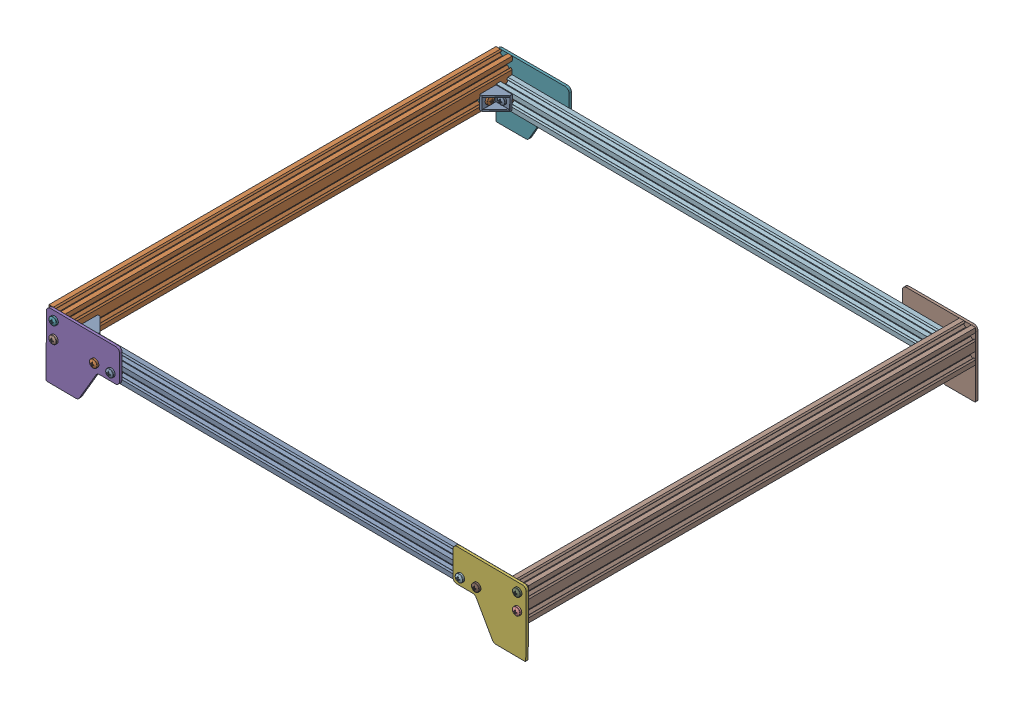
SolidWorks assembly frame, configuration По умолчанию. Lengths in mm.
Overall size (590.6 84.54 563.64).
52 component instances, 7 part files, 101 mates.
Components (placement in the parent):
- 2020 Aluminum Profile_550-3: 2020 Aluminum Profile_550 [По умолчанию] at (869.1226 480.4847 1085.1213) x (0 0 1) z (-0.99997 0.007699 0) size (20 20 550)
- 2040 Aluminum Profile_550_mm-1: 2040 Aluminum Profile_550_mm [По умолчанию] at (309.2932 504.7957 302.3871) x (0.99997 -0.007699 0) z (0 0 1) size (20 40 550)
- 90 Degree Cast Corner for 2020 Extrusion (Ooznest)-1: 90 Degree Cast Corner for 2020 Extrusion (Ooznest) [По умолчанию] at (319.2092 493.8441 1075.1213) x (-0.007699 -0.99997 0) z (0.99997 -0.007699 0) size (17.01 21.05 21.01)
- M5 T-Nut-1: M5 T-Nut [По умолчанию] at (330.8895 484.7539 1077.5213) x (-0.007699 -0.99997 0) z (0 0 -1) size (10 10.5 5)
- M5 T-Nut-2: M5 T-Nut [По умолчанию] at (317.3399 484.8582 1066.1669) x (-0.007699 -0.99997 0) z (0.99997 -0.007699 0) size (10 10.5 5)
- pan cross head_am_B18.6.7M - M5 x 0.8 x 8 Type I Cross Recessed PHMS --8S-1: pan cross head_am_B18.6.7M - M5 x 0.8 x 8 Type I Cross Recessed PHMS --8S [По умолчанию] at (330.8895 484.7539 1068.7213) x (0 0 1) z (-1 0 0) size (11.67 9.5 9.5)
- pan cross head_am_B18.6.7M - M5 x 0.8 x 8 Type I Cross Recessed PHMS --8S-2: pan cross head_am_B18.6.7M - M5 x 0.8 x 8 Type I Cross Recessed PHMS --8S [По умолчанию] at (325.8397 484.7927 1066.1669) x (-0.99997 0.007699 0) z (0.007116 0.924197 0.381849) size (11.67 9.5 9.5)
- M5 T-Nut-3: M5 T-Nut [По умолчанию] at (359.1377 484.4114 1093.3213) x (0 -1 0) z (0 0 1) size (10 10.5 5)
- M5 T-Nut-4: M5 T-Nut [По умолчанию] at (379.1371 484.2574 1093.3213) x (0 -1 0) z (0 0 1) size (10 10.5 5)
- M5 T-Nut-5: M5 T-Nut [По умолчанию] at (829.1238 480.7927 1093.3213) x (0 1 0) z (0 0 1) size (10 10.5 5)
- M5 T-Nut-6: M5 T-Nut [По умолчанию] at (809.1238 480.7927 1093.3213) x (0 -1 0) z (0 0 1) size (10 10.5 5)
- 90 Degree Cast Corner for 2020 Extrusion (Ooznest)-2: 90 Degree Cast Corner for 2020 Extrusion (Ooznest) [По умолчанию] at (319.0783 476.8446 565.1213) x (0.007699 0.99997 0) z (0.99997 -0.007699 0) size (17.01 21.05 21.01)
- M5 T-Nut-7: M5 T-Nut [По умолчанию] at (330.6434 485.2608 563.3213) x (0.007699 0.99997 0) z (0 0 1) size (10 10.5 5)
- 2020 Aluminum Profile_550-2: 2020 Aluminum Profile_550 [По умолчанию] at (310.4341 484.7864 555.1213) x (0 0 -1) z (0.99997 -0.007699 0) size (20 20 550)
- pan cross head_am_B18.6.7M - M5 x 0.8 x 8 Type I Cross Recessed PHMS --8S-3: pan cross head_am_B18.6.7M - M5 x 0.8 x 8 Type I Cross Recessed PHMS --8S [По умолчанию] at (330.6434 485.2608 571.8213) x (0 0 -1) z (1 0 0) size (11.67 9.5 9.5)
- pan cross head_am_B18.6.7M - M5 x 0.8 x 8 Type I Cross Recessed PHMS --8S-4: pan cross head_am_B18.6.7M - M5 x 0.8 x 8 Type I Cross Recessed PHMS --8S [По умолчанию] at (325.8436 485.2978 576.6213) x (-0.99997 0.007699 0) z (-0.007116 -0.924197 0.381849) size (11.67 9.5 9.5)
- M5 T-Nut-8: M5 T-Nut [По умолчанию] at (829.1223 480.4077 547.2213) x (0 -1 0) z (0 0 -1) size (10 10.5 5)
- M5 T-Nut-9: M5 T-Nut [По умолчанию] at (809.1223 480.4077 547.2213) x (0 1 0) z (0 0 -1) size (10 10.5 5)
- M5 T-Nut-10: M5 T-Nut [По умолчанию] at (379.1392 484.7963 546.9213) x (0 1 0) z (0 0 -1) size (10 10.5 5)
- M5 T-Nut-11: M5 T-Nut [По умолчанию] at (359.1392 484.7963 546.9213) x (0 1 0) z (0 0 -1) size (10 10.5 5)
- M5 T-Nut-12: M5 T-Nut [По умолчанию] at (317.0438 485.3655 576.6213) x (0.007699 0.99997 0) z (0.99997 -0.007699 0) size (10 10.5 5)
- 2040 Aluminum Profile_550_mm-2: 2040 Aluminum Profile_550_mm [По умолчанию] at (879.2763 500.4071 1338.0213) x (-0.99997 0.007699 0) z (0 0 -1) size (20 40 550)
- M5 T-Nut-13: M5 T-Nut [По умолчанию] at (871.2238 480.7927 1063.9213) x (0 1 0) z (-1 0 0) size (10 10.5 5)
- pan cross head_am_B18.6.7M - M5 x 0.8 x 8 Type I Cross Recessed PHMS --8S-5: pan cross head_am_B18.6.7M - M5 x 0.8 x 8 Type I Cross Recessed PHMS --8S [По умолчанию] at (857.6238 480.7927 1068.7213) x (0 0 1) z (-1 0 0) size (11.67 9.5 9.5)
- pan cross head_am_B18.6.7M - M5 x 0.8 x 8 Type I Cross Recessed PHMS --8S-6: pan cross head_am_B18.6.7M - M5 x 0.8 x 8 Type I Cross Recessed PHMS --8S [По умолчанию] at (862.4238 480.7927 1063.9213) x (1 0 0) z (0 -0.924225 -0.381849) size (11.67 9.5 9.5)
- pan cross head_am_B18.6.7M - M5 x 0.8 x 8 Type I Cross Recessed PHMS --8S-7: pan cross head_am_B18.6.7M - M5 x 0.8 x 8 Type I Cross Recessed PHMS --8S [По умолчанию] at (857.5886 475.8584 571.8213) x (0 0 -1) z (1 0 0) size (11.67 9.5 9.5)
- pan cross head_am_B18.6.7M - M5 x 0.8 x 8 Type I Cross Recessed PHMS --8S-8: pan cross head_am_B18.6.7M - M5 x 0.8 x 8 Type I Cross Recessed PHMS --8S [По умолчанию] at (862.3894 475.8584 576.6213) x (1 0 0) z (0 0.924225 -0.381849) size (11.67 9.5 9.5)
- M5 T-Nut-14: M5 T-Nut [По умолчанию] at (871.1894 475.8584 576.6213) x (0 -1 0) z (-1 0 0) size (10 10.5 5)
- M5 T-Nut-15: M5 T-Nut [По умолчанию] at (857.5886 475.8584 563.0213) x (0 -1 0) z (0 0 1) size (10 10.5 5)
- M5 T-Nut-16: M5 T-Nut [По умолчанию] at (857.6238 480.7927 1077.5213) x (0 1 0) z (0 0 -1) size (10 10.5 5)
- 90 Degree Cast Corner for 2020 Extrusion (Ooznest)-3: 90 Degree Cast Corner for 2020 Extrusion (Ooznest) [По умолчанию] at (869.1238 489.2927 1075.4213) x (0 -1 0) z (0 0 -1) size (17.01 21.05 21.01)
- 90 Degree Cast Corner for 2020 Extrusion (Ooznest)-4: 90 Degree Cast Corner for 2020 Extrusion (Ooznest) [По умолчанию] at (869.0886 467.3533 565.1213) x (0 1 0) z (0 0 1) size (17.01 21.05 21.01)
- Feet-1: Feet [По умолчанию] at (344.9962 595.9593 1095.2871) x (0.99997 -0.007699 0) z (0 0 1) size (90 80 3)
- Feet-2: Feet [По умолчанию] at (844.9813 592.1097 1098.1213) x (-0.99997 0.007699 0) z (0 0 -1) size (90 80 3)
- pan cross head_am_B18.6.7M - M5 x 0.8 x 10 Type I Cross Recessed PHMS --10S-1: pan cross head_am_B18.6.7M - M5 x 0.8 x 10 Type I Cross Recessed PHMS --10S [По умолчанию] at (309.2932 504.7957 1102.1213) x (0 0 -1) z (1 0 0) size (13.67 9.5 9.5)
- pan cross head_am_B18.6.7M - M5 x 0.8 x 10 Type I Cross Recessed PHMS --10S-2: pan cross head_am_B18.6.7M - M5 x 0.8 x 10 Type I Cross Recessed PHMS --10S [По умолчанию] at (309.1392 484.7963 1102.1213) x (0 0 -1) z (1 0 0) size (13.67 9.5 9.5)
- pan cross head_am_B18.6.7M - M5 x 0.8 x 10 Type I Cross Recessed PHMS --10S-3: pan cross head_am_B18.6.7M - M5 x 0.8 x 10 Type I Cross Recessed PHMS --10S [По умолчанию] at (879.2763 500.4071 1101.8213) x (0 0 -1) z (1 0 0) size (13.67 9.5 9.5)
- pan cross head_am_B18.6.7M - M5 x 0.8 x 10 Type I Cross Recessed PHMS --10S-4: pan cross head_am_B18.6.7M - M5 x 0.8 x 10 Type I Cross Recessed PHMS --10S [По умолчанию] at (879.1223 480.4077 1101.8213) x (0 0 -1) z (1 0 0) size (13.67 9.5 9.5)
- pan cross head_am_B18.6.7M - M5 x 0.8 x 8 Type I Cross Recessed PHMS --8S-9: pan cross head_am_B18.6.7M - M5 x 0.8 x 8 Type I Cross Recessed PHMS --8S [По умолчанию] at (829.1238 480.7927 1102.1213) x (0 0 -1) z (1 0 0) size (11.67 9.5 9.5)
- pan cross head_am_B18.6.7M - M5 x 0.8 x 8 Type I Cross Recessed PHMS --8S-10: pan cross head_am_B18.6.7M - M5 x 0.8 x 8 Type I Cross Recessed PHMS --8S [По умолчанию] at (809.1238 480.7927 1102.1213) x (0 0 -1) z (1 0 0) size (11.67 9.5 9.5)
- pan cross head_am_B18.6.7M - M5 x 0.8 x 8 Type I Cross Recessed PHMS --8S-11: pan cross head_am_B18.6.7M - M5 x 0.8 x 8 Type I Cross Recessed PHMS --8S [По умолчанию] at (379.1371 484.2574 1102.1213) x (0 0 -1) z (1 0 0) size (11.67 9.5 9.5)
- pan cross head_am_B18.6.7M - M5 x 0.8 x 8 Type I Cross Recessed PHMS --8S-12: pan cross head_am_B18.6.7M - M5 x 0.8 x 8 Type I Cross Recessed PHMS --8S [По умолчанию] at (359.1377 484.4114 1102.1213) x (0 0 -1) z (1 0 0) size (11.67 9.5 9.5)
- pan cross head_am_B18.6.7M - M5 x 0.8 x 10 Type I Cross Recessed PHMS --10S-5: pan cross head_am_B18.6.7M - M5 x 0.8 x 10 Type I Cross Recessed PHMS --10S [По умолчанию] at (879.1223 480.4077 538.4213) x (0 0 1) z (1 0 0) size (13.67 9.5 9.5)
- pan cross head_am_B18.6.7M - M5 x 0.8 x 10 Type I Cross Recessed PHMS --10S-6: pan cross head_am_B18.6.7M - M5 x 0.8 x 10 Type I Cross Recessed PHMS --10S [По умолчанию] at (309.1392 504.7963 538.5871) x (0 0 1) z (-1 0 0) size (13.67 9.5 9.5)
- pan cross head_am_B18.6.7M - M5 x 0.8 x 10 Type I Cross Recessed PHMS --10S-7: pan cross head_am_B18.6.7M - M5 x 0.8 x 10 Type I Cross Recessed PHMS --10S [По умолчанию] at (879.1223 500.4077 538.4213) x (0 0 1) z (-1 0 0) size (13.67 9.5 9.5)
- pan cross head_am_B18.6.7M - M5 x 0.8 x 10 Type I Cross Recessed PHMS --10S-8: pan cross head_am_B18.6.7M - M5 x 0.8 x 10 Type I Cross Recessed PHMS --10S [По умолчанию] at (309.1392 484.7963 538.5871) x (0 0 1) z (-1 0 0) size (13.67 9.5 9.5)
- Feet-3: Feet [По умолчанию] at (344.1392 596.2321 542.2871) size (90 80 3)
- Feet-4: Feet [По умолчанию] at (844.1223 591.8435 545.1213) x (-1 0 0) z (0 0 -1) size (90 80 3)
- pan cross head_am_B18.6.7M - M5 x 0.8 x 8 Type I Cross Recessed PHMS --8S-13: pan cross head_am_B18.6.7M - M5 x 0.8 x 8 Type I Cross Recessed PHMS --8S [По умолчанию] at (829.1223 480.4077 538.4213) x (0 0 1) z (-1 0 0) size (11.67 9.5 9.5)
- pan cross head_am_B18.6.7M - M5 x 0.8 x 8 Type I Cross Recessed PHMS --8S-14: pan cross head_am_B18.6.7M - M5 x 0.8 x 8 Type I Cross Recessed PHMS --8S [По умолчанию] at (359.1392 484.7963 538.5871) x (0 0 1) z (-1 0 0) size (11.67 9.5 9.5)
- pan cross head_am_B18.6.7M - M5 x 0.8 x 8 Type I Cross Recessed PHMS --8S-15: pan cross head_am_B18.6.7M - M5 x 0.8 x 8 Type I Cross Recessed PHMS --8S [По умолчанию] at (379.1392 484.7963 538.5871) x (0 0 1) z (-1 0 0) size (11.67 9.5 9.5)
- pan cross head_am_B18.6.7M - M5 x 0.8 x 8 Type I Cross Recessed PHMS --8S-16: pan cross head_am_B18.6.7M - M5 x 0.8 x 8 Type I Cross Recessed PHMS --8S [По умолчанию] at (809.1223 480.4077 538.4213) x (0 0 1) z (-1 0 0) size (11.67 9.5 9.5)
Mates (geometry in assembly coordinates):
- Совпадение1: coincident anti-aligned: plane of 2040 Aluminum Profile_550_mm-2 through (879.2763 500.4071 545.1213) normal (0 0 -1); plane of Feet-4 through (884.1223 505.4077 545.1213) normal (0 0 1)
- Совпадение2: coincident anti-aligned: plane of 2040 Aluminum Profile_550_mm-2 through (879.2763 500.4071 1095.1213) normal (0 0 1); plane of Feet-2 through (884.3147 505.3685 1095.1213) normal (0 0 -1)
- Совпадение3: coincident anti-aligned: plane of 2020 Aluminum Profile_550-3 through (319.1389 484.7193 1085.1213) normal (-0.99997 0.007699 0); plane of 2040 Aluminum Profile_550_mm-1 through (319.0619 474.7196 545.2871) normal (0.99997 -0.007699 0)
- Совпадение4: coincident anti-aligned: plane of 2040 Aluminum Profile_550_mm-1 through (309.2932 504.7957 1095.2871) normal (0 0 1); plane of Feet-1 through (304.3319 509.8341 1095.2871) normal (0 0 -1)
- Совпадение5: coincident anti-aligned: plane of 2020 Aluminum Profile_550-3 through (869.1226 480.4847 1085.1213) normal (0.99997 -0.007699 0); plane of 2040 Aluminum Profile_550_mm-2 through (869.0456 470.485 1095.1213) normal (-0.99997 0.007699 0)
- Совпадение8: coincident aligned: circle of 2040 Aluminum Profile_550_mm-2; circle of Feet-2
- Совпадение9: coincident anti-aligned: plane of 2020 Aluminum Profile_550-3 through (319.163 487.8442 1093.3213) normal (0 0 -1); plane of M5 T-Nut-6 through (814.3738 483.7927 1093.3213) normal (0 0 1)
- Совпадение11: coincident anti-aligned: plane of 2020 Aluminum Profile_550-3 through (319.1037 480.1395 1095.1213) normal (0 0 1); plane of Feet-2 through (884.3147 505.3685 1095.1213) normal (0 0 -1)
- Совпадение14: coincident anti-aligned: plane of 2040 Aluminum Profile_550_mm-2 through (879.2763 500.4071 545.1213) normal (0 0 -1); plane of Feet-4 through (884.1223 505.4077 545.1213) normal (0 0 1)
- Совпадение15: coincident aligned: circle of 2040 Aluminum Profile_550_mm-2; circle of Feet-4
- Совпадение16: coincident: plane of 2040 Aluminum Profile_550_mm-1 through (309.2932 504.7957 545.2871) normal (0 0 -1); plane of Feet-3 through (304.1392 509.7963 545.2871) normal (0 0 1)
- Совпадение17: coincident: cylinder of 2040 Aluminum Profile_550_mm-1 through (309.1392 484.7963 545.2871) axis (0 0 1) radius 2.55; circle of Feet-3
- Совпадение23: coincident: plane of Feet-3 through (304.1392 509.7963 542.2871) normal (0 0 -1); plane of pan cross head_am_B18.6.7M - M5 x 0.8 x 8 Type I Cross Recessed PHMS --8S-15 through (379.1392 487.2963 542.2871) normal (0 0 1)
- Совпадение25: coincident: plane of Feet-3 through (304.1392 509.7963 542.2871) normal (0 0 -1); plane of pan cross head_am_B18.6.7M - M5 x 0.8 x 8 Type I Cross Recessed PHMS --8S-14 through (359.1392 487.2963 542.2871) normal (0 0 1)
- Совпадение26: coincident: line of 2020 Aluminum Profile_550-2 through (860.4419 483.6766 546.9213) axis (-0.99997 0.007699 0); plane of M5 T-Nut-10 through (384.3892 489.7963 546.9213) normal (0 0 -1)
- Совпадение28: coincident anti-aligned: plane of pan cross head_am_B18.6.7M - M5 x 0.8 x 10 Type I Cross Recessed PHMS --10S-6 through (309.1392 507.2963 542.2871) normal (0 0 1); plane of Feet-3 through (304.1392 509.7963 542.2871) normal (0 0 -1)
- Совпадение30: coincident anti-aligned: plane of pan cross head_am_B18.6.7M - M5 x 0.8 x 10 Type I Cross Recessed PHMS --10S-8 through (309.1392 487.2963 542.2871) normal (0 0 1); plane of Feet-3 through (304.1392 509.7963 542.2871) normal (0 0 -1)
- Совпадение32: coincident anti-aligned: plane of pan cross head_am_B18.6.7M - M5 x 0.8 x 10 Type I Cross Recessed PHMS --10S-7 through (879.1223 502.9077 542.1213) normal (0 0 1); plane of Feet-4 through (884.1223 505.4077 542.1213) normal (0 0 -1)
- Параллельность11: parallel anti-aligned: plane of pan cross head_am_B18.6.7M - M5 x 0.8 x 10 Type I Cross Recessed PHMS --10S-5 through (879.1223 477.9077 542.1213) normal (0 0 1); plane of Feet-4 through (884.1223 505.4077 542.1213) normal (0 0 -1)
- Совпадение34: coincident: plane of M5 T-Nut-10 through (384.3892 487.7963 545.9213) normal (0 0 -1); plane of M5 T-Nut-11 through (364.3892 487.7963 545.9213) normal (0 0 -1)
- Расстояние1: distance = 3.25 mm aligned: plane of 90 Degree Cast Corner for 2020 Extrusion (Ooznest)-2 through (339.0777 476.6906 565.1213) normal (0.99997 -0.007699 0); plane of M5 T-Nut-7 through (335.8933 485.2204 562.0708) normal (0.99997 -0.007699 0)
- Расстояние4: distance = 3.25 mm: plane of 90 Degree Cast Corner for 2020 Extrusion (Ooznest)-2 through (329.1434 485.2673 585.1213) normal (0 0 1); plane of M5 T-Nut-12 through (315.7934 485.3752 581.8713) normal (0 0 1)
- Концентричный2: concentric aligned: circle of pan cross head_am_B18.6.7M - M5 x 0.8 x 8 Type I Cross Recessed PHMS --8S-4; circle of M5 T-Nut-12
- Концентричный3: concentric aligned: circle of M5 T-Nut-7; circle of pan cross head_am_B18.6.7M - M5 x 0.8 x 8 Type I Cross Recessed PHMS --8S-3
- Совпадение40: coincident: plane of 90 Degree Cast Corner for 2020 Extrusion (Ooznest)-2 through (330.6434 485.2558 568.1213) normal (0 0 1); plane of pan cross head_am_B18.6.7M - M5 x 0.8 x 8 Type I Cross Recessed PHMS --8S-3 through (330.6434 487.7608 568.1213) normal (0 0 -1)
- Совпадение43: coincident: plane of M5 T-Nut-7 through (325.3705 482.3013 563.3213) normal (0 0 1); line of 2020 Aluminum Profile_550-2 through (860.3938 477.4268 563.3213) axis (-0.99997 0.007699 0)
- Совпадение44: coincident anti-aligned: plane of Feet-2 through (884.3147 505.3685 1098.1213) normal (0 0 1); plane of pan cross head_am_B18.6.7M - M5 x 0.8 x 10 Type I Cross Recessed PHMS --10S-3 through (879.2763 502.9071 1098.1213) normal (0 0 -1)
- Совпадение45: coincident aligned: plane of pan cross head_am_B18.6.7M - M5 x 0.8 x 10 Type I Cross Recessed PHMS --10S-3 through (879.2763 502.9071 1098.1213) normal (0 0 -1); plane of pan cross head_am_B18.6.7M - M5 x 0.8 x 10 Type I Cross Recessed PHMS --10S-4 through (879.1223 482.9077 1098.1213) normal (0 0 -1)
- Концентричный4: concentric anti-aligned: circle of Feet-2; circle of pan cross head_am_B18.6.7M - M5 x 0.8 x 10 Type I Cross Recessed PHMS --10S-3
- Концентричный5: concentric anti-aligned: circle of Feet-2; circle of pan cross head_am_B18.6.7M - M5 x 0.8 x 10 Type I Cross Recessed PHMS --10S-4
- Концентричный6: concentric: circle of M5 T-Nut-6; circle of pan cross head_am_B18.6.7M - M5 x 0.8 x 8 Type I Cross Recessed PHMS --8S-10
- Расстояние5: distance = 1.1 mm: plane of pan cross head_am_B18.6.7M - M5 x 0.8 x 8 Type I Cross Recessed PHMS --8S-10 through (809.1238 483.2927 1090.4213) normal (0 0 -1); plane of M5 T-Nut-6 through (814.3738 483.2927 1089.3213) normal (0 0 -1)
- Расстояние6: distance = 1.1 mm: plane of M5 T-Nut-5 through (823.8738 478.2927 1089.3213) normal (0 0 -1); plane of pan cross head_am_B18.6.7M - M5 x 0.8 x 8 Type I Cross Recessed PHMS --8S-9 through (829.1238 483.2927 1090.4213) normal (0 0 -1)
- Концентричный7: concentric: circle of M5 T-Nut-5; circle of pan cross head_am_B18.6.7M - M5 x 0.8 x 8 Type I Cross Recessed PHMS --8S-9
- Концентричный8: concentric anti-aligned: circle of Feet-2; circle of pan cross head_am_B18.6.7M - M5 x 0.8 x 8 Type I Cross Recessed PHMS --8S-9
- Концентричный9: concentric aligned: circle of pan cross head_am_B18.6.7M - M5 x 0.8 x 10 Type I Cross Recessed PHMS --10S-5; circle of Feet-4
- Совпадение46: coincident anti-aligned: plane of pan cross head_am_B18.6.7M - M5 x 0.8 x 10 Type I Cross Recessed PHMS --10S-5 through (879.1223 477.9077 542.1213) normal (0 0 1); plane of Feet-4 through (884.1223 505.4077 542.1213) normal (0 0 -1)
- Концентричный10: concentric anti-aligned: circle of M5 T-Nut-9; circle of pan cross head_am_B18.6.7M - M5 x 0.8 x 8 Type I Cross Recessed PHMS --8S-16
- Расстояние7: distance = 1.1 mm aligned: plane of pan cross head_am_B18.6.7M - M5 x 0.8 x 8 Type I Cross Recessed PHMS --8S-16 through (809.1223 482.9077 550.1213) normal (0 0 1); plane of M5 T-Nut-9 through (814.3723 477.9077 551.2213) normal (0 0 1)
- Расстояние8: distance = 1.1 mm aligned: plane of pan cross head_am_B18.6.7M - M5 x 0.8 x 8 Type I Cross Recessed PHMS --8S-13 through (829.1223 482.9077 550.1213) normal (0 0 1); plane of M5 T-Nut-8 through (823.8723 482.9077 551.2213) normal (0 0 1)
- Концентричный11: concentric aligned: circle of M5 T-Nut-8; circle of pan cross head_am_B18.6.7M - M5 x 0.8 x 8 Type I Cross Recessed PHMS --8S-13
- Концентричный13: concentric aligned: circle of Feet-4; circle of pan cross head_am_B18.6.7M - M5 x 0.8 x 8 Type I Cross Recessed PHMS --8S-13
- Совпадение47: coincident anti-aligned: plane of Feet-4 through (884.1223 505.4077 542.1213) normal (0 0 -1); plane of pan cross head_am_B18.6.7M - M5 x 0.8 x 8 Type I Cross Recessed PHMS --8S-13 through (829.1223 482.9077 542.1213) normal (0 0 1)
- Совпадение48: coincident anti-aligned: plane of Feet-4 through (884.1223 505.4077 542.1213) normal (0 0 -1); plane of pan cross head_am_B18.6.7M - M5 x 0.8 x 8 Type I Cross Recessed PHMS --8S-16 through (809.1223 482.9077 542.1213) normal (0 0 1)
- Расстояние9: distance = 1.1 mm aligned: plane of pan cross head_am_B18.6.7M - M5 x 0.8 x 8 Type I Cross Recessed PHMS --8S-8 through (874.0894 474.9038 574.3107) normal (1 0 0); plane of M5 T-Nut-14 through (875.1894 478.3584 581.8713) normal (1 0 0)
- Расстояние10: distance = 1.1 mm aligned: plane of pan cross head_am_B18.6.7M - M5 x 0.8 x 8 Type I Cross Recessed PHMS --8S-7 through (857.5886 478.3584 560.1213) normal (0 0 -1); plane of M5 T-Nut-15 through (862.8386 478.3584 559.0213) normal (0 0 -1)
- Расстояние11: distance = 6.25 mm aligned: plane of M5 T-Nut-15 through (862.8386 475.8584 561.7708) normal (1 0 0); plane of 90 Degree Cast Corner for 2020 Extrusion (Ooznest)-4 through (869.0886 475.8533 575.1213) normal (1 0 0)
- Расстояние12: distance = 6.25 mm aligned: plane of M5 T-Nut-14 through (872.4398 475.8584 571.3713) normal (0 0 -1); plane of 90 Degree Cast Corner for 2020 Extrusion (Ooznest)-4 through (869.0886 484.3533 565.1213) normal (0 0 -1)
- Расстояние13: distance = 3.495 mm aligned: plane of M5 T-Nut-14 through (871.1894 480.8584 581.8713) normal (0 1 0); plane of 90 Degree Cast Corner for 2020 Extrusion (Ooznest)-4 through (869.0886 484.3533 585.1213) normal (0 1 0)
- Расстояние14: distance = 3.495 mm aligned: plane of M5 T-Nut-15 through (862.8386 480.8584 563.0213) normal (0 1 0); plane of 90 Degree Cast Corner for 2020 Extrusion (Ooznest)-4 through (869.0886 484.3533 585.1213) normal (0 1 0)
- Концентричный14: concentric anti-aligned: circle of pan cross head_am_B18.6.7M - M5 x 0.8 x 8 Type I Cross Recessed PHMS --8S-7; circle of M5 T-Nut-15
- Концентричный15: concentric anti-aligned: circle of pan cross head_am_B18.6.7M - M5 x 0.8 x 8 Type I Cross Recessed PHMS --8S-8; circle of M5 T-Nut-14
- Совпадение49: coincident anti-aligned: plane of 2020 Aluminum Profile_550-2 through (860.3408 470.552 565.1213) normal (0 0 1); plane of 90 Degree Cast Corner for 2020 Extrusion (Ooznest)-4 through (869.0886 484.3533 565.1213) normal (0 0 -1)
- Совпадение50: coincident anti-aligned: plane of pan cross head_am_B18.6.7M - M5 x 0.8 x 8 Type I Cross Recessed PHMS --8S-7 through (857.5886 478.3584 568.1213) normal (0 0 -1); plane of 90 Degree Cast Corner for 2020 Extrusion (Ooznest)-4 through (849.0886 469.3533 568.1213) normal (0 0 1)
- Расстояние16: distance = 6.25 mm: plane of 90 Degree Cast Corner for 2020 Extrusion (Ooznest)-2 through (329.1434 485.2673 565.1213) normal (0 0 -1); plane of M5 T-Nut-12 through (315.7934 485.3752 571.3713) normal (0 0 -1)
- Расстояние17: distance = 3.495 mm aligned: plane of M5 T-Nut-7 through (325.4321 490.3011 563.3213) normal (0.007699 0.99997 0); plane of 90 Degree Cast Corner for 2020 Extrusion (Ooznest)-2 through (339.2086 493.6901 565.1213) normal (0.007699 0.99997 0)
- Расстояние18: distance = 3.495 mm aligned: plane of M5 T-Nut-12 through (317.0823 490.3654 581.8713) normal (0.007699 0.99997 0); plane of 90 Degree Cast Corner for 2020 Extrusion (Ooznest)-2 through (339.2086 493.6901 565.1213) normal (0.007699 0.99997 0)
- Расстояние19: distance = 1.1 mm aligned: plane of pan cross head_am_B18.6.7M - M5 x 0.8 x 8 Type I Cross Recessed PHMS --8S-4 through (314.1366 484.4333 574.3107) normal (-0.99997 0.007699 0); plane of M5 T-Nut-12 through (313.0247 482.8964 581.8713) normal (-0.99997 0.007699 0)
- Расстояние20: distance = 0.8 mm: plane of pan cross head_am_B18.6.7M - M5 x 0.8 x 8 Type I Cross Recessed PHMS --8S-3 through (330.6434 487.7608 560.1213) normal (0 0 -1); plane of M5 T-Nut-7 through (325.3743 482.8013 559.3213) normal (0 0 -1)
- Концентричный16: concentric anti-aligned: circle of pan cross head_am_B18.6.7M - M5 x 0.8 x 8 Type I Cross Recessed PHMS --8S-4; circle of M5 T-Nut-12
- Концентричный17: concentric anti-aligned: circle of M5 T-Nut-7; circle of pan cross head_am_B18.6.7M - M5 x 0.8 x 8 Type I Cross Recessed PHMS --8S-3
- Совпадение56: coincident anti-aligned: plane of 90 Degree Cast Corner for 2020 Extrusion (Ooznest)-2 through (322.0936 478.8214 585.1213) normal (0.99997 -0.007699 0); plane of pan cross head_am_B18.6.7M - M5 x 0.8 x 8 Type I Cross Recessed PHMS --8S-4 through (322.1363 484.3717 574.3107) normal (-0.99997 0.007699 0)
- Совпадение60: coincident anti-aligned: plane of 2040 Aluminum Profile_550_mm-1 through (319.1742 489.2992 545.2871) normal (0.99997 -0.007699 0); plane of 90 Degree Cast Corner for 2020 Extrusion (Ooznest)-2 through (319.2092 493.8441 565.1213) normal (-0.99997 0.007699 0)
- Совпадение61: coincident: plane of 90 Degree Cast Corner for 2020 Extrusion (Ooznest)-2 through (329.1434 485.2673 565.1213) normal (0 0 -1); plane of 2020 Aluminum Profile_550-2 through (860.3408 470.552 565.1213) normal (0 0 1)
- Совпадение63: coincident anti-aligned: plane of 2020 Aluminum Profile_550-2 through (860.4948 490.5514 545.1213) normal (0 0 -1); plane of Feet-4 through (884.1223 505.4077 545.1213) normal (0 0 1)
- Совпадение64: coincident aligned: plane of 2020 Aluminum Profile_550-2 through (860.3408 470.552 559.7013) normal (-0.007699 -0.99997 0); plane of 2040 Aluminum Profile_550_mm-2 through (889.045 470.331 1095.1213) normal (-0.007699 -0.99997 0)
- Концентричный18: concentric aligned: circle of Feet-4; circle of pan cross head_am_B18.6.7M - M5 x 0.8 x 8 Type I Cross Recessed PHMS --8S-16
- Концентричный19: concentric aligned: circle of pan cross head_am_B18.6.7M - M5 x 0.8 x 10 Type I Cross Recessed PHMS --10S-7; circle of Feet-4
- Совпадение65: coincident aligned: plane of 2040 Aluminum Profile_550_mm-1 through (299.0625 474.8736 545.2871) normal (-0.007699 -0.99997 0); plane of 2020 Aluminum Profile_550-2 through (860.3408 470.552 545.1213) normal (-0.007699 -0.99997 0)
- Совпадение66: coincident aligned: plane of 2020 Aluminum Profile_550-3 through (319.0619 474.7196 1095.1213) normal (-0.007699 -0.99997 0); plane of 2040 Aluminum Profile_550_mm-1 through (299.0625 474.8736 545.2871) normal (-0.007699 -0.99997 0)
- Концентричный20: concentric anti-aligned: circle of 2040 Aluminum Profile_550_mm-2; circle of pan cross head_am_B18.6.7M - M5 x 0.8 x 10 Type I Cross Recessed PHMS --10S-4
- Параллельность19: parallel aligned: plane of 90 Degree Cast Corner for 2020 Extrusion (Ooznest)-1 through (319.2092 493.8441 1075.1213) normal (0.007699 0.99997 0); plane of Feet-1 through (384.368 514.218 1098.2871) normal (0.007699 0.99997 0)
- Параллельность20: parallel aligned: plane of 90 Degree Cast Corner for 2020 Extrusion (Ooznest)-1 through (319.0783 476.8446 1075.1213) normal (-0.99997 0.007699 0); plane of Feet-1 through (298.7623 435.8748 1098.2871) normal (-0.99997 0.007699 0)
- Концентричный22: concentric aligned: circle of 2040 Aluminum Profile_550_mm-1; circle of pan cross head_am_B18.6.7M - M5 x 0.8 x 10 Type I Cross Recessed PHMS --10S-1
- Концентричный24: concentric aligned: circle of Feet-1; circle of pan cross head_am_B18.6.7M - M5 x 0.8 x 10 Type I Cross Recessed PHMS --10S-1
- Расстояние25: distance = 1.1 mm aligned: plane of pan cross head_am_B18.6.7M - M5 x 0.8 x 8 Type I Cross Recessed PHMS --8S-12 through (359.1377 486.9114 1090.4213) normal (0 0 -1); plane of M5 T-Nut-3 through (364.3877 486.9114 1089.3213) normal (0 0 -1)
- Концентричный25: concentric anti-aligned: circle of M5 T-Nut-3; circle of pan cross head_am_B18.6.7M - M5 x 0.8 x 8 Type I Cross Recessed PHMS --8S-12
- Расстояние26: distance = 1.1 mm aligned: plane of pan cross head_am_B18.6.7M - M5 x 0.8 x 8 Type I Cross Recessed PHMS --8S-11 through (379.1371 486.7574 1090.4213) normal (0 0 -1); plane of M5 T-Nut-4 through (384.3871 486.7574 1089.3213) normal (0 0 -1)
- Концентричный26: concentric anti-aligned: circle of M5 T-Nut-4; circle of pan cross head_am_B18.6.7M - M5 x 0.8 x 8 Type I Cross Recessed PHMS --8S-11
- Концентричный27: concentric aligned: circle of Feet-1; circle of pan cross head_am_B18.6.7M - M5 x 0.8 x 8 Type I Cross Recessed PHMS --8S-11
- Концентричный28: concentric aligned: circle of Feet-1; circle of pan cross head_am_B18.6.7M - M5 x 0.8 x 8 Type I Cross Recessed PHMS --8S-12
- Концентричный29: concentric aligned: circle of Feet-1; circle of pan cross head_am_B18.6.7M - M5 x 0.8 x 10 Type I Cross Recessed PHMS --10S-2
- Концентричный30: concentric anti-aligned: circle of pan cross head_am_B18.6.7M - M5 x 0.8 x 10 Type I Cross Recessed PHMS --10S-6; circle of Feet-3
- Концентричный31: concentric anti-aligned: circle of pan cross head_am_B18.6.7M - M5 x 0.8 x 10 Type I Cross Recessed PHMS --10S-8; circle of Feet-3
- Расстояние27: distance = 0.6342 mm: plane of pan cross head_am_B18.6.7M - M5 x 0.8 x 8 Type I Cross Recessed PHMS --8S-14 through (359.1392 487.2963 550.2871) normal (0 0 1); plane of M5 T-Nut-11 through (364.3892 482.2963 550.9213) normal (0 0 1)
- Расстояние28: distance = 0.6342 mm: plane of M5 T-Nut-10 through (384.3892 482.2963 550.9213) normal (0 0 1); plane of pan cross head_am_B18.6.7M - M5 x 0.8 x 8 Type I Cross Recessed PHMS --8S-15 through (379.1392 487.2963 550.2871) normal (0 0 1)
- Концентричный32: concentric anti-aligned: circle of M5 T-Nut-10; circle of pan cross head_am_B18.6.7M - M5 x 0.8 x 8 Type I Cross Recessed PHMS --8S-15
- Концентричный33: concentric anti-aligned: circle of M5 T-Nut-11; circle of pan cross head_am_B18.6.7M - M5 x 0.8 x 8 Type I Cross Recessed PHMS --8S-14
- Концентричный34: concentric anti-aligned: circle of Feet-3; circle of pan cross head_am_B18.6.7M - M5 x 0.8 x 8 Type I Cross Recessed PHMS --8S-15
- Концентричный35: concentric anti-aligned: circle of Feet-3; circle of pan cross head_am_B18.6.7M - M5 x 0.8 x 8 Type I Cross Recessed PHMS --8S-14
- Совпадение72: coincident anti-aligned: plane of 90 Degree Cast Corner for 2020 Extrusion (Ooznest)-1 through (322.1937 491.821 1055.1213) normal (0.99997 -0.007699 0); plane of pan cross head_am_B18.6.7M - M5 x 0.8 x 8 Type I Cross Recessed PHMS --8S-2 through (322.1325 483.8666 1068.4774) normal (-0.99997 0.007699 0)
- Расстояние29: distance = 7 mm: cylinder of pan cross head_am_B18.6.7M - M5 x 0.8 x 8 Type I Cross Recessed PHMS --8S-2 through (351.2389 484.5972 1066.1669) axis (0.99997 -0.007699 0) radius 4.75; plane of 90 Degree Cast Corner for 2020 Extrusion (Ooznest)-1 through (339.1932 491.6901 1055.1213) normal (-0.007699 -0.99997 0)
- Расстояние30: distance = 3 mm aligned: plane of M5 T-Nut-1 through (336.1394 484.7134 1078.7717) normal (0.99997 -0.007699 0); plane of 90 Degree Cast Corner for 2020 Extrusion (Ooznest)-1 through (339.2086 493.6901 1075.1213) normal (0.99997 -0.007699 0)
- Совпадение77: coincident anti-aligned: plane of 2020 Aluminum Profile_550-3 through (319.163 487.8442 1076.9213) normal (-0.007699 -0.99997 0); plane of M5 T-Nut-1 through (325.6628 487.7942 1076.5213) normal (0.007699 0.99997 0)
- Концентричный37: concentric aligned: circle of M5 T-Nut-1; circle of pan cross head_am_B18.6.7M - M5 x 0.8 x 8 Type I Cross Recessed PHMS --8S-1
- Параллельность21: parallel aligned: plane of 90 Degree Cast Corner for 2020 Extrusion (Ooznest)-1 through (319.2092 493.8441 1075.1213) normal (0.007699 0.99997 0); plane of M5 T-Nut-2 through (317.3784 489.858 1060.9169) normal (0.007699 0.99997 0)
- Совпадение79: coincident anti-aligned: plane of 2040 Aluminum Profile_550_mm-1 through (317.3813 490.233 545.2871) normal (-0.99997 0.007699 0); plane of M5 T-Nut-2 through (317.363 487.8581 1060.9169) normal (0.99997 -0.007699 0)
- Совпадение85: coincident anti-aligned: plane of 2040 Aluminum Profile_550_mm-1 through (317.363 487.8581 545.2871) normal (-0.007699 -0.99997 0); plane of M5 T-Nut-2 through (318.363 487.8504 1060.9169) normal (0.007699 0.99997 0)
- Совпадение86: coincident aligned: plane of 90 Degree Cast Corner for 2020 Extrusion (Ooznest)-1 through (319.2092 493.8441 1075.1213) normal (0.007699 0.99997 0); plane of 90 Degree Cast Corner for 2020 Extrusion (Ooznest)-2 through (339.2086 493.6901 565.1213) normal (0.007699 0.99997 0)
- Концентричный39: concentric aligned: circle of M5 T-Nut-2; circle of pan cross head_am_B18.6.7M - M5 x 0.8 x 8 Type I Cross Recessed PHMS --8S-2
- Совпадение87: coincident anti-aligned: plane of 2020 Aluminum Profile_550-3 through (319.1742 489.2992 1075.1213) normal (0 0 -1); plane of 90 Degree Cast Corner for 2020 Extrusion (Ooznest)-1 through (329.1434 485.2673 1075.1213) normal (0 0 1)
